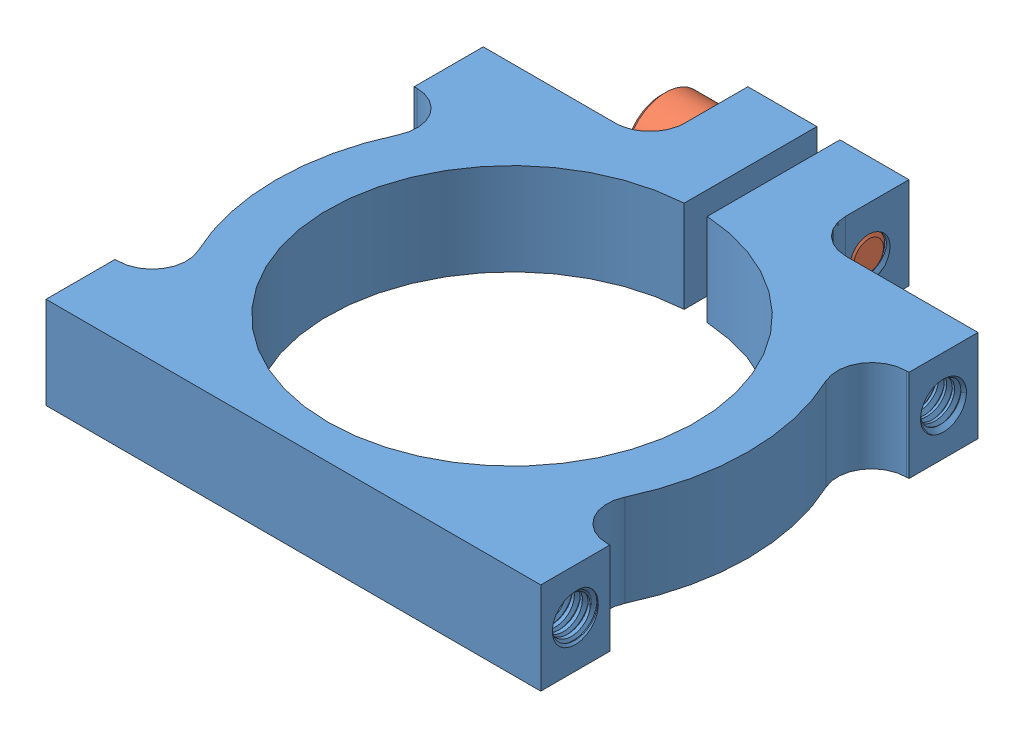
SolidWorks assembly 1401-0043-0032 assembly, configuration Default. Lengths in mm.
Overall size (43.01 8.04 47.02).
3 component instances, 2 part files, 0 mates.
Components (placement in the parent):
- 1401-0043-0032 assembly.STEP-1: 1401-0043-0032 assembly.STEP [Default] at origin size (43.01 8.04 47.02)
  - 1401-0043-0032.STEP-1: 1401-0043-0032.STEP [Default] at (0.7931 12.12 -4.4026) size (43.01 8 46.5)
  - 2800-0004-0014_90128A207.STEP-1: 2800-0004-0014_90128A207.STEP [Default] at (7.7931 12.12 -28.4026) x (0 0.161804 -0.986823) z (1 0 0) size (7 7 18.01)
